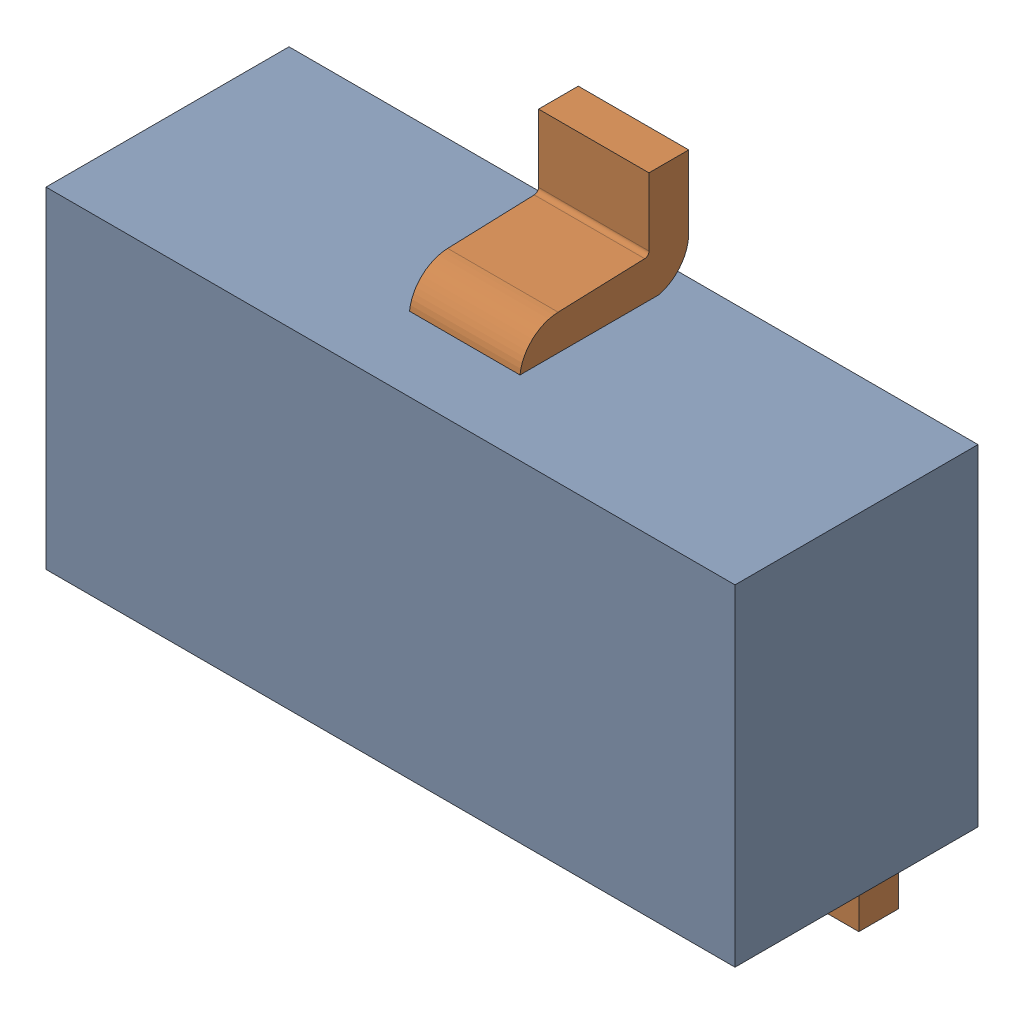
SolidWorks assembly Q1, configuration Default. Lengths in mm.
Overall size (3.12 2.5 1.1).
3 component instances, 2 part files, 0 mates.
Components (placement in the parent):
- 1737248328-1: 1737248328 [Default] at (2 2.775 0) size (3.12 1.5 1.1)
  - Extruded-2-1: Extruded-2 [Default] at origin size (3.12 1.5 1.1)
- SOT23-3_TO-236AB-1: SOT23-3_TO-236AB [Default] at (2 2.7751 0) x (-1 0 0) z (0 1 0) size (3 1.09 2.5)
